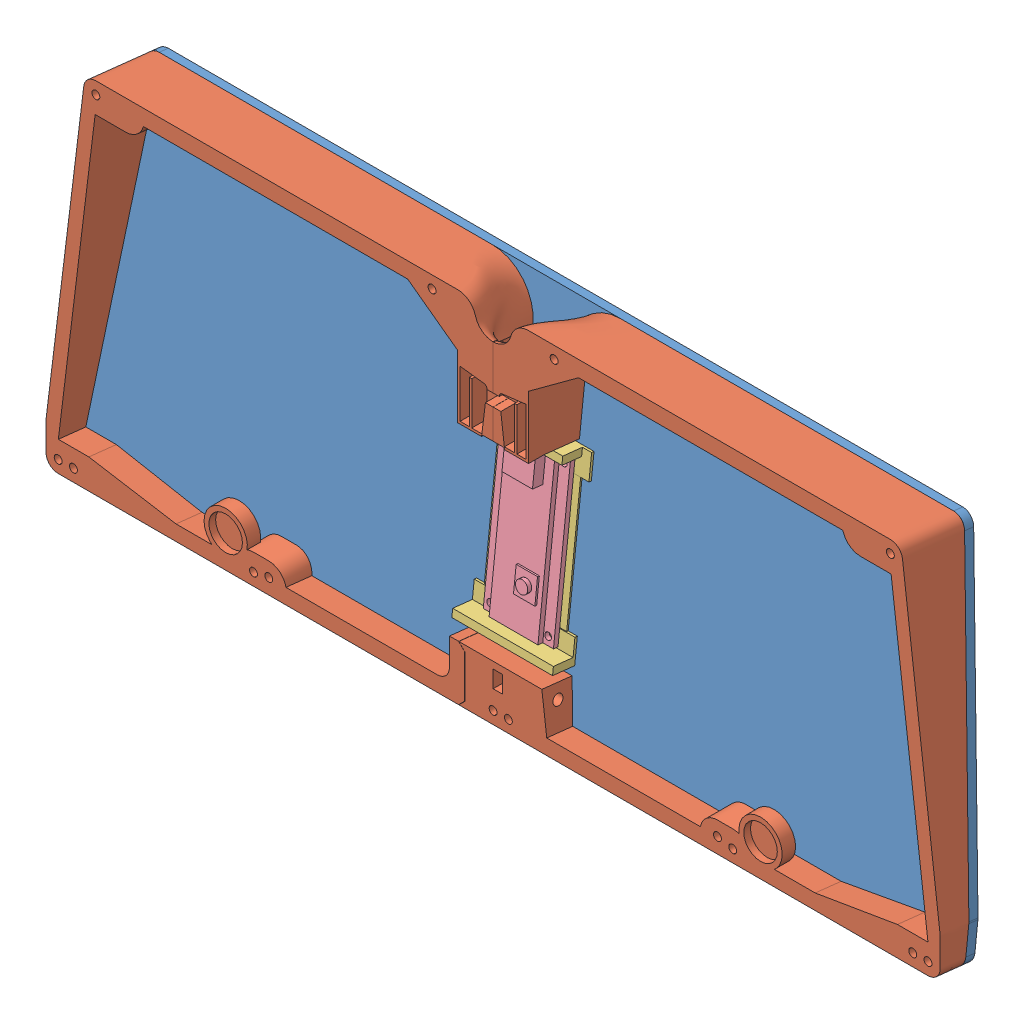
SolidWorks assembly Planka-assem_3dprint, configuration Default. Lengths in mm.
Overall size (293.13 118.88 24.25).
25 component instances, 6 part files, 72 mates.
Components (placement in the parent):
- Planka-top-1: Planka-top [Default] at origin size (296.39 117.67 3) (hidden)
- Planka-3d_bottom_plate-1: Planka-3d_bottom_plate [Default] at (0 0 -11.4504) x (1 0 0) z (0 0.109407 0.993997) size (293.11 116.96 3)
- Planka-3d_frame-1: Planka-3d_frame [Default] at (0 -3.6527 -3) size (293.13 118.56 21.28)
- Planka-3d_Controller_spacer-1: Planka-3d_Controller_spacer [Default] at (-11.5 71.1326 -16.9658) x (0 -0.993997 0.109407) z (0 0.109407 0.993997) size (58 33 7.3)
- AdaFruit_controller_PCB-1: AdaFruit_controller_PCB [Default] at (-11.5 71.1326 -16.9658) x (0 -0.993997 0.109407) z (0 0.109407 0.993997) size (55.1 23 6.5)
- CherryMX key cutout_v12-1: CherryMX key cutout_v12 [Plate 3_6_6_ minmum heght] at (-124.9732 91.1095 0) x (0.992546 -0.121869 0) z (-0.121869 -0.992546 0) size (15.6 9 16) (hidden)
- CherryMX key cutout_v12-6: CherryMX key cutout_v12 [Plate 3_6_6_ minmum heght] at (-127.2948 72.2015 0) x (0.992546 -0.121869 0) z (-0.121869 -0.992546 0) size (15.6 9 16) (hidden)
- CherryMX key cutout_v12-7: CherryMX key cutout_v12 [Plate 3_6_6_ minmum heght] at (-129.6164 53.2935 0) x (0.992546 -0.121869 0) z (-0.121869 -0.992546 0) size (15.6 9 16) (hidden)
- CherryMX key cutout_v12-8: CherryMX key cutout_v12 [Plate 3_6_6_ minmum heght] at (-131.938 34.3855 0) x (0.992546 -0.121869 0) z (-0.121869 -0.992546 0) size (15.6 9 16) (hidden)
- CherryMX key cutout_v12-9: CherryMX key cutout_v12 [Plate 3_6_6_ minmum heght] at (-134.2596 15.4775 0) x (0.992546 -0.121869 0) z (-0.121869 -0.992546 0) size (15.6 9 16) (hidden)
- CherryMX key cutout_v12-10: CherryMX key cutout_v12 [Plate 3_6_6_ minmum heght] at (-115.2298 14.1484 0) x (0.992546 -0.121869 0) z (-0.121869 -0.992546 0) size (15.6 9 16) (hidden)
- CherryMX key cutout_v12-11: CherryMX key cutout_v12 [Plate 3_6_6_ minmum heght] at (-24.6283 9.5426 0) x (0.992546 -0.121869 0) z (-0.121869 -0.992546 0) size (15.6 9 16) (hidden)
- CherryMX key cutout_v12-12: CherryMX key cutout_v12 [Plate 3_6_6_ minmum heght] at (-66.1774 101.018 0) x (0.992546 -0.121869 0) z (-0.121869 -0.992546 0) size (15.6 9 16) (hidden)
- CherryMX key cutout_v12-13: CherryMX key cutout_v12 [Plate 3_6_6_ minmum heght] at (-85.5442 99.6026 0) x (0.992546 -0.121869 0) z (-0.121869 -0.992546 0) size (15.6 9 16) (hidden)
- CherryMX key cutout_v12-14: CherryMX key cutout_v12 [Plate 3_6_6_ minmum heght] at (-10.6148 84.5942 0) x (0.992546 -0.121869 0) z (-0.121869 -0.992546 0) size (15.6 9 16) (hidden)
- CherryMX key cutout_v12-15: CherryMX key cutout_v12 [Plate 3_6_6_ minmum heght] at (10.6148 84.5942 0) x (0.992546 0.121869 0) z (0.121869 -0.992546 0) size (15.6 9 16) (hidden)
- CherryMX key cutout_v12-16: CherryMX key cutout_v12 [Plate 3_6_6_ minmum heght] at (66.1774 101.018 0) x (0.992546 0.121869 0) z (0.121869 -0.992546 0) size (15.6 9 16) (hidden)
- CherryMX key cutout_v12-17: CherryMX key cutout_v12 [Plate 3_6_6_ minmum heght] at (24.6283 9.5426 0) x (0.992546 0.121869 0) z (0.121869 -0.992546 0) size (15.6 9 16) (hidden)
- CherryMX key cutout_v12-18: CherryMX key cutout_v12 [Plate 3_6_6_ minmum heght] at (134.2596 15.4775 0) x (0.992546 0.121869 0) z (0.121869 -0.992546 0) size (15.6 9 16) (hidden)
- CherryMX key cutout_v12-19: CherryMX key cutout_v12 [Plate 3_6_6_ minmum heght] at (124.9732 91.1095 0) x (0.992546 0.121869 0) z (0.121869 -0.992546 0) size (15.6 9 16) (hidden)
- CherryMX key cutout_v12-20: CherryMX key cutout_v12 [Plate 3_6_6_ minmum heght] at (127.2948 72.2015 0) x (0.992546 0.121869 0) z (0.121869 -0.992546 0) size (15.6 9 16) (hidden)
- CherryMX key cutout_v12-21: CherryMX key cutout_v12 [Plate 3_6_6_ minmum heght] at (129.6164 53.2935 0) x (0.992546 0.121869 0) z (0.121869 -0.992546 0) size (15.6 9 16) (hidden)
- CherryMX key cutout_v12-22: CherryMX key cutout_v12 [Plate 3_6_6_ minmum heght] at (131.938 34.3855 0) x (0.992546 0.121869 0) z (0.121869 -0.992546 0) size (15.6 9 16) (hidden)
- CherryMX key cutout_v12-23: CherryMX key cutout_v12 [Plate 3_6_6_ minmum heght] at (85.5442 99.6026 0) x (0.992546 0.121869 0) z (0.121869 -0.992546 0) size (15.6 9 16) (hidden)
- CherryMX key cutout_v12-24: CherryMX key cutout_v12 [Plate 3_6_6_ minmum heght] at (115.2298 14.1484 0) x (0.992546 0.121869 0) z (0.121869 -0.992546 0) size (15.6 9 16) (hidden)
Mates (geometry in assembly coordinates):
- Coincident1: coordinate: point of Planka-top-1; point of assembly
- Coincident2: coincident aligned: plane of Planka-3d_bottom_plate-1 through (0 0 -11.4504) normal (0 0.109407 0.993997); plane of assembly through (0 -1.2452 -11.3133) normal (0 0.109407 0.993997)
- Coincident5: coincident aligned: plane of Planka-top-1 through (0 0 0) normal (1 0 0); plane of Planka-3d_bottom_plate-1
- Coincident6: coincident: plane of Planka-top-1 through (0 0 0) normal (0 1 0); point of Planka-3d_bottom_plate-1
- Parallel2: parallel aligned: plane of AdaFruit_controller_PCB-1; plane of assembly through (0 0 0) normal (1 0 0)
- Distance1: distance = 0.8 mm anti-aligned: plane of Planka-3d_bottom_plate-1 through (-142.5568 -0.5758 -11.387) normal (0 0.109407 0.993997); plane of AdaFruit_controller_PCB-1 through (-11.5 70.9685 -18.4568) normal (0 -0.109407 -0.993997)
- Symmetric2: symmetric anti-aligned: line of ? through (-11.5 71.1326 -16.9658) axis (0 -0.993997 0.109407); line of ? through (11.5 19.4447 -11.2767) axis (0 0.993997 -0.109407)
- Coincident11: coincident: plane of ? through (-11.5 74.214 -17.305) normal (0 0.993997 -0.109407)
- Coincident12: coincident anti-aligned: plane of Planka-top-1 through (11.619 108.018 -3) normal (0 0 -1); plane of Planka-3d_frame-1 through (0 -3.6527 -3) normal (0 0 1)
- Coincident14: coincident: moEndPointRef_w of Planka-top-1; point of Planka-3d_frame-1
- Coincident15: coincident aligned: plane of Planka-top-1 through (0 0 0) normal (1 0 0); plane of Planka-3d_frame-1 through (0 -3.6527 -3) normal (1 0 0)
- Coincident28: coincident: point of Planka-top-1; point of CherryMX key cutout_v12-1
- Parallel9: parallel: plane of Planka-top-1 through (11.619 108.018 0) normal (0 0 1); line of CherryMX key cutout_v12-1 through (-133.6656 84.3182 0) axis (0.992546 -0.121869 0)
- Parallel10: parallel anti-aligned: line of Planka-top-1 through (-134.1378 16.47 0) axis (0.121869 0.992546 0); line of CherryMX key cutout_v12-1 through (-124.0226 98.8514 0) axis (-0.121869 -0.992546 0)
- Parallel11: parallel: plane of Planka-top-1 through (11.619 108.018 0) normal (0 0 1); line of CherryMX key cutout_v12-6 through (-135.9872 65.4102 0) axis (0.992546 -0.121869 0)
- Parallel12: parallel anti-aligned: line of Planka-top-1 through (-134.1378 16.47 0) axis (0.121869 0.992546 0); line of CherryMX key cutout_v12-6 through (-126.3442 79.9434 0) axis (-0.121869 -0.992546 0)
- Coincident31: coincident: point of Planka-top-1; point of CherryMX key cutout_v12-6
- Coincident32: coincident: point of Planka-top-1; point of CherryMX key cutout_v12-7
- Parallel13: parallel: plane of Planka-top-1 through (11.619 108.018 0) normal (0 0 1); line of CherryMX key cutout_v12-7 through (-138.3089 46.5022 0) axis (0.992546 -0.121869 0)
- Parallel14: parallel anti-aligned: line of Planka-top-1 through (-134.1378 16.47 0) axis (0.121869 0.992546 0); line of CherryMX key cutout_v12-7 through (-128.6658 61.0354 0) axis (-0.121869 -0.992546 0)
- Coincident33: coincident: point of Planka-top-1; point of CherryMX key cutout_v12-8
- Parallel15: parallel: plane of Planka-top-1 through (11.619 108.018 0) normal (0 0 1); line of CherryMX key cutout_v12-8 through (-140.6305 27.5942 0) axis (0.992546 -0.121869 0)
- Parallel16: parallel anti-aligned: line of Planka-top-1 through (-134.1378 16.47 0) axis (0.121869 0.992546 0); line of CherryMX key cutout_v12-8 through (-130.9874 42.1274 0) axis (-0.121869 -0.992546 0)
- Coincident34: coincident: point of Planka-top-1; point of CherryMX key cutout_v12-9
- Parallel17: parallel: plane of Planka-top-1 through (11.619 108.018 0) normal (0 0 1); line of CherryMX key cutout_v12-9 through (-142.9521 8.6862 0) axis (0.992546 -0.121869 0)
- Parallel18: parallel anti-aligned: line of Planka-top-1 through (-134.1378 16.47 0) axis (0.121869 0.992546 0); line of CherryMX key cutout_v12-9 through (-133.3091 23.2194 0) axis (-0.121869 -0.992546 0)
- Coincident35: coincident: point of Planka-top-1; point of CherryMX key cutout_v12-10
- Parallel19: parallel: plane of Planka-top-1 through (11.619 108.018 0) normal (0 0 1); line of CherryMX key cutout_v12-10 through (-123.9222 7.3572 0) axis (0.992546 -0.121869 0)
- Parallel20: parallel anti-aligned: line of Planka-top-1 through (-134.1378 16.47 0) axis (0.121869 0.992546 0); line of CherryMX key cutout_v12-10 through (-114.2792 21.8903 0) axis (-0.121869 -0.992546 0)
- Coincident36: coincident: point of Planka-top-1; point of CherryMX key cutout_v12-11
- Parallel21: parallel: plane of Planka-top-1 through (11.619 108.018 0) normal (0 0 1); line of CherryMX key cutout_v12-11 through (-33.3207 2.7513 0) axis (0.992546 -0.121869 0)
- Parallel22: parallel anti-aligned: line of Planka-top-1 through (-134.1378 16.47 0) axis (0.121869 0.992546 0); line of CherryMX key cutout_v12-11 through (-23.6777 17.2844 0) axis (-0.121869 -0.992546 0)
- Coincident37: coincident: point of Planka-top-1; point of CherryMX key cutout_v12-12
- Parallel23: parallel: plane of Planka-top-1 through (11.619 108.018 0) normal (0 0 1); line of CherryMX key cutout_v12-12 through (-74.8698 94.2267 0) axis (0.992546 -0.121869 0)
- Parallel24: parallel anti-aligned: line of Planka-top-1 through (-134.1378 16.47 0) axis (0.121869 0.992546 0); line of CherryMX key cutout_v12-12 through (-65.2268 108.7598 0) axis (-0.121869 -0.992546 0)
- Coincident38: coincident: point of Planka-top-1; point of CherryMX key cutout_v12-13
- Parallel25: parallel: plane of Planka-top-1 through (11.619 108.018 0) normal (0 0 1); line of CherryMX key cutout_v12-13 through (-94.2367 92.8114 0) axis (0.992546 -0.121869 0)
- Parallel26: parallel anti-aligned: line of Planka-top-1 through (-134.1378 16.47 0) axis (0.121869 0.992546 0); line of CherryMX key cutout_v12-13 through (-84.5937 107.3445 0) axis (-0.121869 -0.992546 0)
- Coincident39: coincident: point of Planka-top-1; point of CherryMX key cutout_v12-14
- Parallel27: parallel: plane of Planka-top-1 through (11.619 108.018 0) normal (0 0 1); line of CherryMX key cutout_v12-14 through (-19.3072 77.8029 0) axis (0.992546 -0.121869 0)
- Parallel28: parallel anti-aligned: line of Planka-top-1 through (-134.1378 16.47 0) axis (0.121869 0.992546 0); line of CherryMX key cutout_v12-14 through (-9.6642 92.336 0) axis (-0.121869 -0.992546 0)
- Coincident40: coincident: point of Planka-top-1; point of CherryMX key cutout_v12-15
- Parallel29: parallel: plane of Planka-top-1 through (11.619 108.018 0) normal (0 0 1); line of CherryMX key cutout_v12-15 through (3.8235 75.9017 0) axis (0.992546 0.121869 0)
- Parallel31: parallel anti-aligned: line of Planka-top-1 through (20.6897 2.5404 0) axis (-0.121869 0.992546 0); line of CherryMX key cutout_v12-15 through (9.6642 92.336 0) axis (0.121869 -0.992546 0)
- Coincident41: coincident: point of Planka-top-1; point of CherryMX key cutout_v12-16
- Parallel32: parallel: plane of Planka-top-1 through (11.619 108.018 0) normal (0 0 1); line of CherryMX key cutout_v12-16 through (59.3861 92.3255 0) axis (0.992546 0.121869 0)
- Parallel33: parallel anti-aligned: line of Planka-top-1 through (20.6897 2.5404 0) axis (-0.121869 0.992546 0); line of CherryMX key cutout_v12-16 through (65.2268 108.7598 0) axis (0.121869 -0.992546 0)
- Coincident42: coincident: point of Planka-top-1; point of CherryMX key cutout_v12-17
- Parallel34: parallel: plane of Planka-top-1 through (11.619 108.018 0) normal (0 0 1); line of CherryMX key cutout_v12-17 through (17.837 0.8501 0) axis (0.992546 0.121869 0)
- Parallel35: parallel anti-aligned: line of Planka-top-1 through (20.6897 2.5404 0) axis (-0.121869 0.992546 0); line of CherryMX key cutout_v12-17 through (23.6777 17.2844 0) axis (0.121869 -0.992546 0)
- Coincident43: coincident: point of Planka-top-1; point of CherryMX key cutout_v12-18
- Parallel36: parallel: plane of Planka-top-1 through (11.619 108.018 0) normal (0 0 1); line of CherryMX key cutout_v12-18 through (127.4684 6.7851 0) axis (0.992546 0.121869 0)
- Parallel37: parallel anti-aligned: line of Planka-top-1 through (20.6897 2.5404 0) axis (-0.121869 0.992546 0); line of CherryMX key cutout_v12-18 through (133.3091 23.2194 0) axis (0.121869 -0.992546 0)
- Coincident44: coincident: point of Planka-top-1; point of CherryMX key cutout_v12-19
- Parallel38: parallel: plane of Planka-top-1 through (11.619 108.018 0) normal (0 0 1); line of CherryMX key cutout_v12-19 through (118.1819 82.4171 0) axis (0.992546 0.121869 0)
- Parallel39: parallel anti-aligned: line of Planka-top-1 through (20.6897 2.5404 0) axis (-0.121869 0.992546 0); line of CherryMX key cutout_v12-19 through (124.0226 98.8514 0) axis (0.121869 -0.992546 0)
- Coincident45: coincident: point of Planka-top-1; point of CherryMX key cutout_v12-20
- Parallel40: parallel: plane of Planka-top-1 through (11.619 108.018 0) normal (0 0 1); line of CherryMX key cutout_v12-20 through (120.5035 63.5091 0) axis (0.992546 0.121869 0)
- Parallel41: parallel anti-aligned: line of Planka-top-1 through (20.6897 2.5404 0) axis (-0.121869 0.992546 0); line of CherryMX key cutout_v12-20 through (126.3442 79.9434 0) axis (0.121869 -0.992546 0)
- Coincident46: coincident: point of Planka-top-1; point of CherryMX key cutout_v12-21
- Parallel42: parallel: plane of Planka-top-1 through (11.619 108.018 0) normal (0 0 1); line of CherryMX key cutout_v12-21 through (122.8251 44.6011 0) axis (0.992546 0.121869 0)
- Parallel43: parallel anti-aligned: line of Planka-top-1 through (20.6897 2.5404 0) axis (-0.121869 0.992546 0); line of CherryMX key cutout_v12-21 through (128.6658 61.0354 0) axis (0.121869 -0.992546 0)
- Coincident47: coincident: point of Planka-top-1; point of CherryMX key cutout_v12-22
- Parallel44: parallel: plane of Planka-top-1 through (11.619 108.018 0) normal (0 0 1); line of CherryMX key cutout_v12-22 through (125.1468 25.6931 0) axis (0.992546 0.121869 0)
- Parallel45: parallel anti-aligned: line of Planka-top-1 through (20.6897 2.5404 0) axis (-0.121869 0.992546 0); line of CherryMX key cutout_v12-22 through (130.9874 42.1274 0) axis (0.121869 -0.992546 0)
- Coincident48: coincident: point of Planka-top-1; point of CherryMX key cutout_v12-23
- Parallel46: parallel: plane of Planka-top-1 through (11.619 108.018 0) normal (0 0 1); line of CherryMX key cutout_v12-23 through (78.753 90.9102 0) axis (0.992546 0.121869 0)
- Parallel47: parallel anti-aligned: line of Planka-top-1 through (20.6897 2.5404 0) axis (-0.121869 0.992546 0); line of CherryMX key cutout_v12-23 through (84.5937 107.3445 0) axis (0.121869 -0.992546 0)
- Parallel48: parallel: plane of Planka-top-1 through (11.619 108.018 0) normal (0 0 1); line of CherryMX key cutout_v12-24 through (108.4385 5.456 0) axis (0.992546 0.121869 0)
- Parallel49: parallel anti-aligned: line of Planka-top-1 through (20.6897 2.5404 0) axis (-0.121869 0.992546 0); line of CherryMX key cutout_v12-24 through (114.2792 21.8903 0) axis (0.121869 -0.992546 0)
- Coincident49: coincident: point of Planka-top-1; point of CherryMX key cutout_v12-24
- Coincident54: coordinate: point of Planka-3d_Controller_spacer-1; point of AdaFruit_controller_PCB-1
